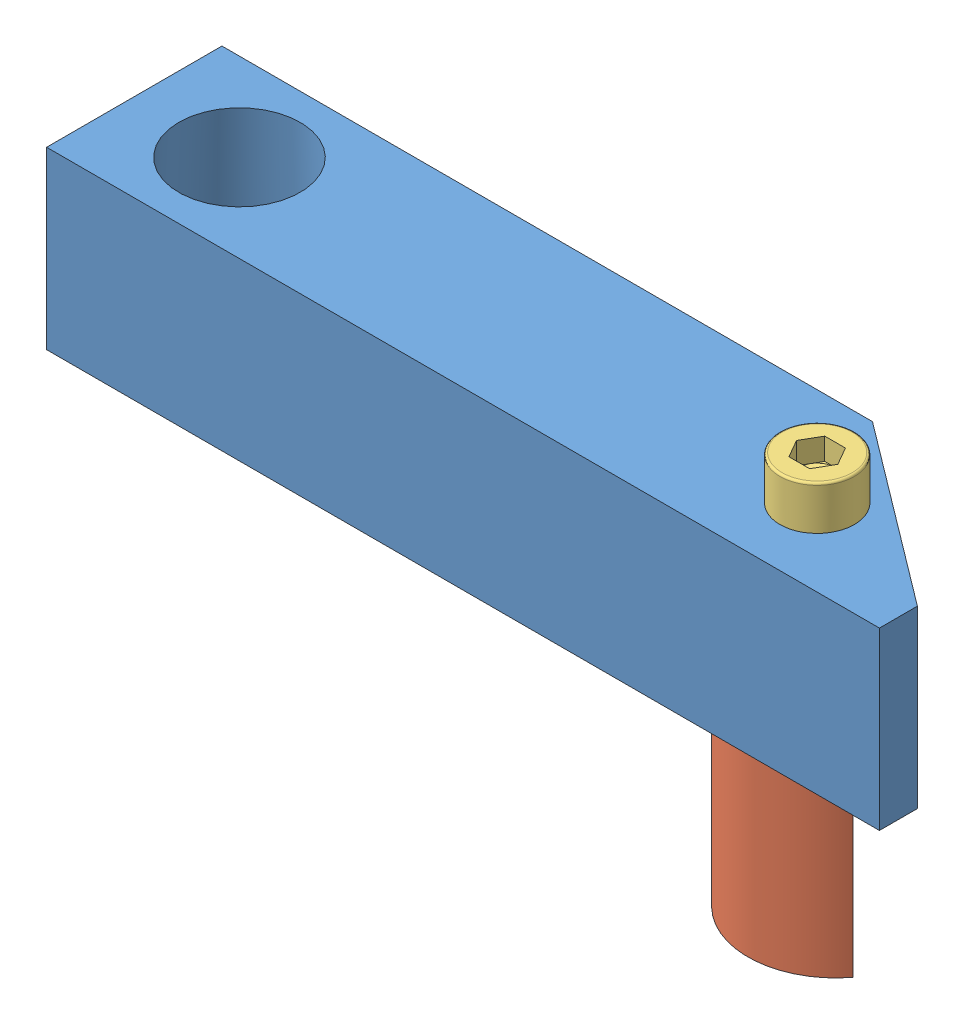
SolidWorks assembly assemb_braco_v2, configuration Default. Lengths in mm.
Overall size (95 45 24).
3 component instances, 3 part files, 6 mates.
Components (placement in the parent):
- clamping_arm_sp_v2-1: clamping_arm_sp_v2 [Default] at (-9.7899 71.0887 70.2446) x (1 0 0) z (0 1 0) size (95 20 20)
- contact_end_spec-1: contact_end_spec [Default] at (58.2101 31.0887 70.2446) x (0.601815 0 -0.798636) z (0.798636 0 0.601815) size (14.5 35 20)
- socket head cap screw_iso-1: socket head cap screw_iso [ISO 4762 M5 x 12 - 12N] at (57.3074 76.0887 71.4426) x (0 -1 0) z (0 0 1) size (17 8.5 8.5)
Mates (geometry in assembly coordinates):
- Concentric1: concentric aligned: cylinder of clamping_arm_sp_v2-1 through (58.2101 66.0887 70.2446) axis (0 -1 0) radius 7.5; cylinder of contact_end_spec-1 through (58.2101 66.0887 70.2446) axis (0 -1 0) radius 7.5
- Coincident1: coincident aligned: plane of clamping_arm_sp_v2-1 through (73.2101 71.0887 75.9133) normal (0.601815 0 -0.798636); plane of contact_end_spec-1 through (66.908 66.0887 71.1644) normal (0.601815 0 -0.798636)
- Coincident2: coincident anti-aligned: plane of clamping_arm_sp_v2-1 through (58.2101 66.0887 70.2446) normal (0 -1 0); plane of contact_end_spec-1 through (58.2101 66.0887 70.2446) normal (0 1 0)
- Concentric2: concentric anti-aligned: cylinder of clamping_arm_sp_v2-1 through (57.3074 81.0887 71.4426) axis (0 -1 0) radius 2.75; cylinder of socket head cap screw_iso-1 through (57.3074 107.8387 71.4426) axis (0 1 0) radius 4.25
- Coincident3: coincident anti-aligned: plane of clamping_arm_sp_v2-1 through (-21.7899 71.0887 80.2446) normal (0 1 0); plane of socket head cap screw_iso-1 through (61.5574 71.0887 71.4426) normal (0 -1 0)
- Coincident4: coincident anti-aligned: plane of clamping_arm_sp_v2-1 through (73.2101 71.0887 75.9133) normal (0.601815 0 -0.798636); plane of socket head cap screw_iso-2 through (58.4945 72.9544 64.8243) normal (-0.601815 0 0.798636)
